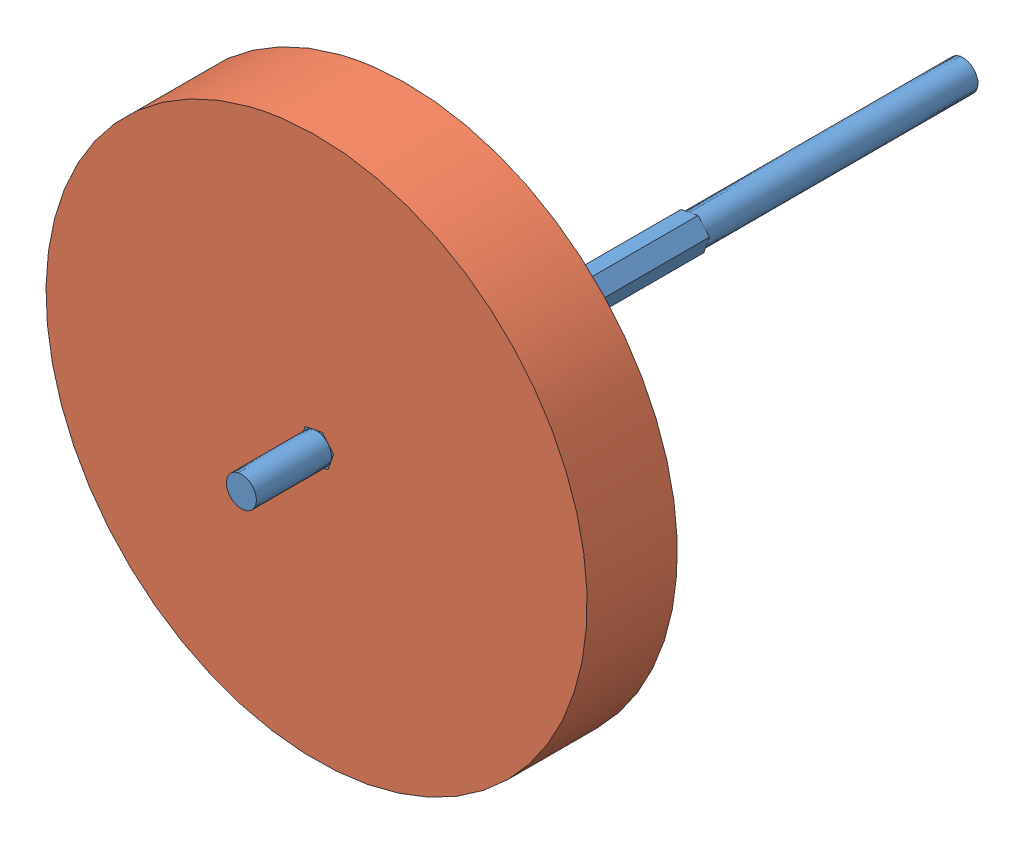
SolidWorks assembly Drivetrain wheel axle and belt gear driven, configuration Default. Lengths in mm.
Overall size (133.9 133.9 133.35).
3 component instances, 3 part files, 9 mates.
Components (placement in the parent):
- wheel axle-1: wheel axle [Default] at (0 57.15 34.925) x (-0.189612 0.981859 0) z (0 0 -1) size (6.35 7.33 133.35)
- Wheel-1: Wheel [Default] at (0 57.15 19.05) x (-0.189612 0.981859 0) z (0 0 -1) size (114.3 114.3 19.05)
- belt gear-2: belt gear [Default] at (0 57.15 -12.7) x (-0.189612 0.981859 0) z (0 0 1) size (39.94 39.94 6.35)
Mates (geometry in assembly coordinates):
- Coincident1: coincident: plane of wheel axle-1 through (3.5997 57.8451 -98.425) normal (0.945121 -0.326721 0); plane of Wheel-1 through (2.4019 54.3802 0) normal (-0.945121 0.326721 0)
- Coincident2: coincident: plane of wheel axle-1 through (-2.4019 59.9198 -98.425) normal (-0.189612 0.981859 0); plane of Wheel-1 through (1.1978 60.615 0) normal (0.189612 -0.981859 0)
- Coincident3: coincident: circle of Wheel-1; point of assembly
- Tangent1: tangent: cylinder of Wheel-1 through (0 57.15 0) axis (0 0 1) radius 57.15; plane of assembly through (0 0 0) normal (0 1 0)
- Parallel1: parallel: plane of Wheel-1 through (0 57.15 19.05) normal (0 0 1); plane of assembly through (0 0 0) normal (0 0 1)
- Coincident5: coincident: plane of wheel axle-1 through (1.1978 60.615 -98.425) normal (0.755509 0.655138 0); plane of belt gear-2 through (3.5997 57.8451 -6.35) normal (-0.755509 -0.655138 0)
- Coincident6: coincident: plane of wheel axle-1 through (3.5997 57.8451 -98.425) normal (0.945121 -0.326721 0); plane of belt gear-2 through (2.4019 54.3802 -6.35) normal (-0.945121 0.326721 0)
- Coincident7: coincident: plane of wheel axle-1 through (0 57.15 19.05) normal (0 0 1); plane of Wheel-1 through (0 57.15 19.05) normal (0 0 1)
- Distance1: distance = 6.35 mm: plane of belt gear-2 through (0 57.15 -6.35) normal (0 0 1); plane of Wheel-1 through (0 57.15 0) normal (0 0 -1)
